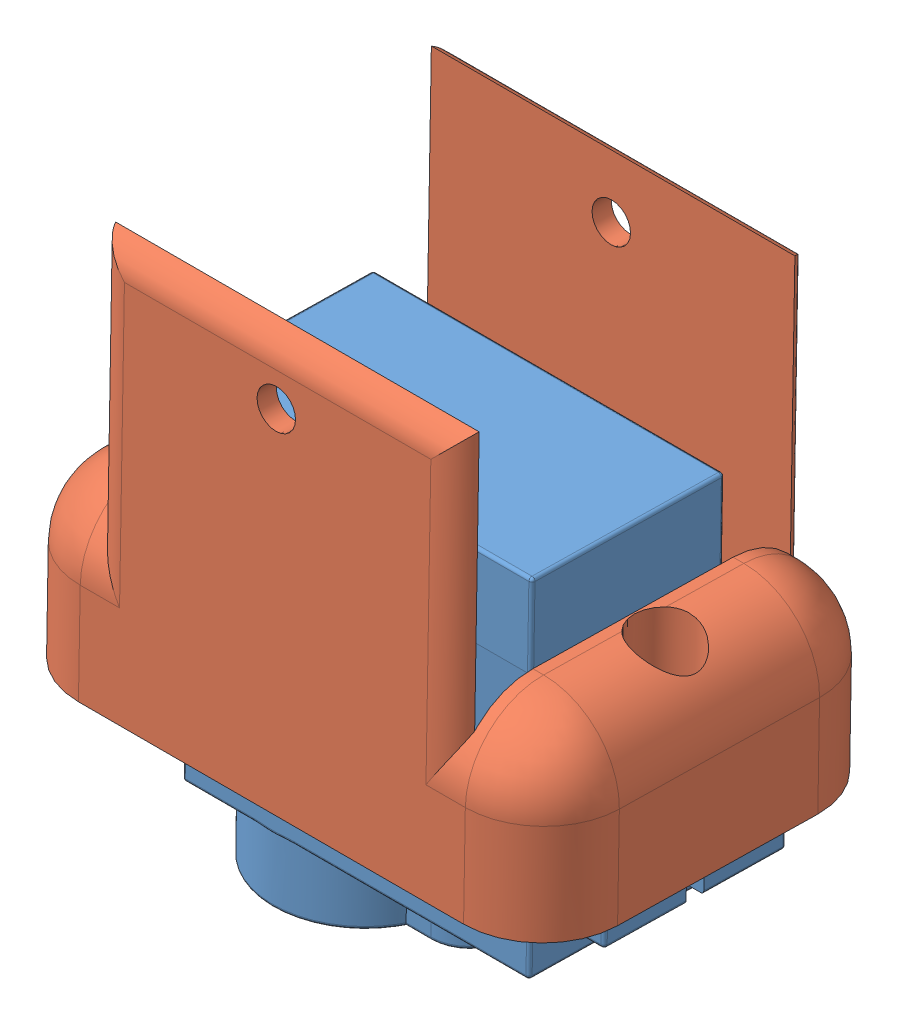
SolidWorks assembly BaseServoMountAssem1, configuration Default. Lengths in mm.
Overall size (35 37.42 23.46).
2 component instances, 2 part files, 2 mates.
Components (placement in the parent):
- Part1-1: Part1 [Default] at (9.6338 -16.7881 -7.4322) x (1 0 0) z (0 -0.017452 -0.999848) size (32.1 26.81 12.5)
- BaseServoMount-1: BaseServoMount [Default] at (20.8233 -16.686 -1.5831) x (1 0 0) z (0 0.999848 -0.017452) size (35 23 26.5)
Mates (geometry in assembly coordinates):
- Coincident2: coincident anti-aligned: plane of Part1-1 through (9.6338 -16.7881 -7.4322) normal (0 0.999848 -0.017452); plane of BaseServoMount-1 through (20.8233 -16.686 -1.5831) normal (0 -0.999848 0.017452)
- Distance1: distance = 0.3 mm anti-aligned: plane of BaseServoMount-1 through (9.0233 -14.0773 4.6223) normal (0 -0.017452 -0.999848); plane of Part1-1 through (4.8338 -22.9812 4.4777) normal (0 0.017452 0.999848)
